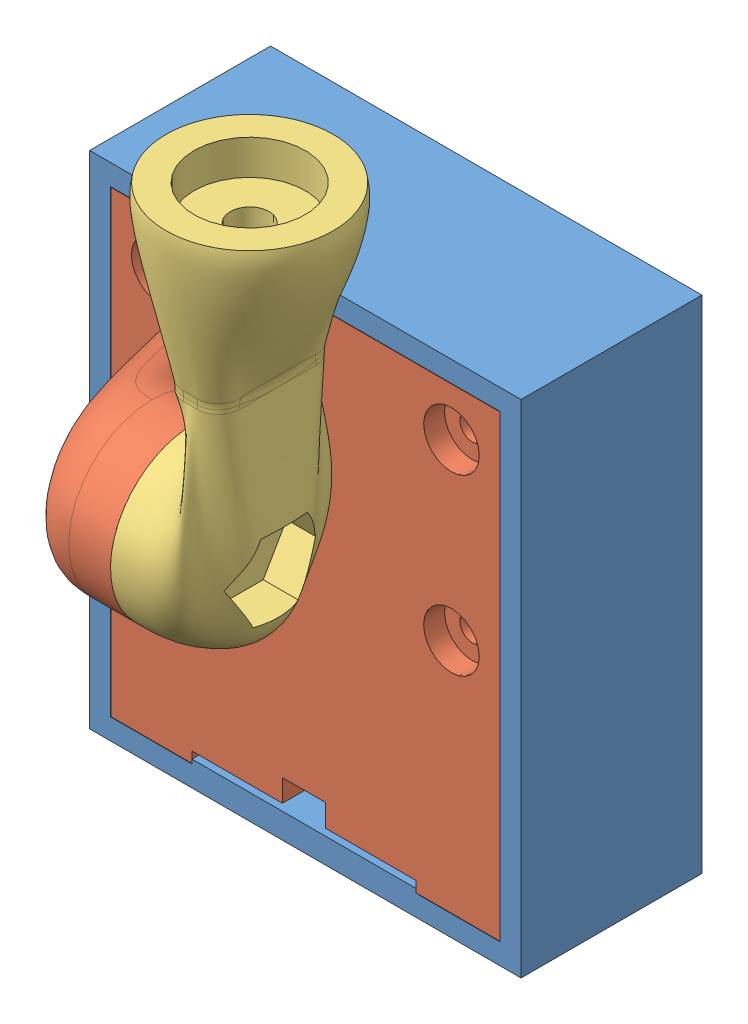
SolidWorks assembly Cubre camara, configuration Predeterminado. Lengths in mm.
Overall size (31 47.76 27.2).
3 component instances, 3 part files, 5 mates.
Components (placement in the parent):
- Tapa Camara-1: Tapa Camara [Predeterminado] at (-10.8149 0.4135 31.75) size (31 36 13)
- Base Camara-1: Base Camara [Predeterminado] at origin size (27.94 32.94 21.4)
- Brazo-1: Brazo [Predeterminado] at origin size (13.16 29.04 12.21)
Mates (geometry in assembly coordinates):
- Concéntrica1: concentric aligned: cylinder of Pieza2-1 through (-10.8149 0.4135 33.25) axis (0 0 -1) radius 3.65; circle of RasPi_Camera-1/OVA5647-2/OVA5647_Lens-1
- Paralelo1: parallel aligned: plane of Pieza2-1 through (4.6851 -10.0865 40.25) normal (1 0 0); plane of RasPi_Camera-1/RasPi_Camera_Board-1 through (1.6536 14.8548 37.05) normal (1 0 0)
- Coincidente3: coincident anti-aligned: plane of Pieza2-1 through (-0.3149 -0.5865 36.15) normal (0 0 1); plane of RasPi_Camera-1/RasPi_Camera_Board-1 through (-10.8464 0.3548 36.15) normal (0 0 -1)
- Concéntrica2: concentric aligned: cylinder of Pieza2-1 through (-0.0149 -13.7365 31.75) axis (0 0 1) radius 2.65; cylinder of 5mmLED-1 through (-0.0149 -13.7365 39.25) axis (0 0 1) radius 2.5
- Coincidente5: coincident anti-aligned: plane of Pieza2-1 through (-10.8149 0.4135 38.25) normal (0 0 1); plane of 5mmLED-1 through (-0.0149 -13.7365 38.25) normal (0 0 -1)
